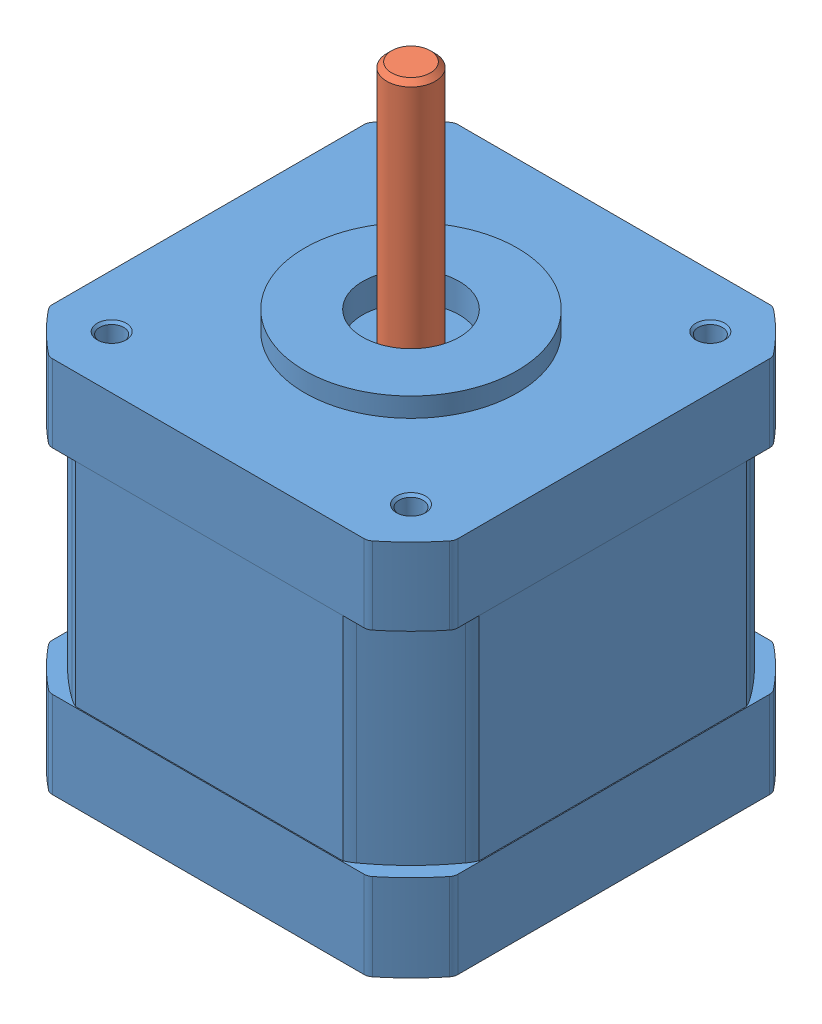
SolidWorks assembly Stepper_motor_NEMA17, configuration Default. Lengths in mm.
Overall size (42 63.3 42).
2 component instances, 2 part files, 10 mates.
Components (placement in the parent):
- Stator-1: Stator [Default] at origin size (42 41.1 42)
- Rotor-1: Rotor [Default] x (0.508449 0 0.861092) z (-0.861092 0 0.508449) size (21 60.8 21)
Mates (geometry in assembly coordinates):
- InPlace1: in place: plane of Stator-1 through (0 0 0) normal (0 0 1); moOrthogonalPlaneRef_w of Stator-1 through (0 0 0) normal (0 1 0); plane of Stator-1 through (0 0 0) normal (1 0 0); unknown of Stator-1
- Coincident1: coincident aligned: plane of Stator-1; plane of assembly
- Coincident2: coincident aligned: plane of Stator-1 through (0 0 0) normal (0 1 0); moOrthogonalPlaneRef_w of assembly
- Coincident3: coincident anti-aligned: plane of Stator-1 through (0 0 0) normal (1 0 0); moOrthogonalPlaneRef_w of assembly
- InPlace2: in place: plane of Stator-1 through (0 0 0) normal (0 0 1); plane of Stator-1 through (0 0 0) normal (0 1 0); plane of Stator-1 through (0 0 0) normal (1 0 0); unknown of Stator-1
- Coincident1: coincident aligned: plane of Rotor-1; plane of assembly
- Coincident2: coincident aligned: line of Stator-1 through (-11.55 0 0) axis (0 0 1)
- Coincident3: coincident anti-aligned: line of Stator-1 through (33.44 -33.44 0) axis (0 0 1)
- Distance1: distance = 0.5 mm anti-aligned: plane of Stator-1 through (2.5 -32.1 0) normal (0 1 0); plane of Rotor-1 through (1.2711 -31.6 2.1527) normal (0 -1 0)
- Concentric1: concentric aligned: cylinder of Stator-1 through (0 0 0) axis (0 1 0) radius 2.5; cylinder of Rotor-1 through (0 22.2 0) axis (0 1 0) radius 2.5
